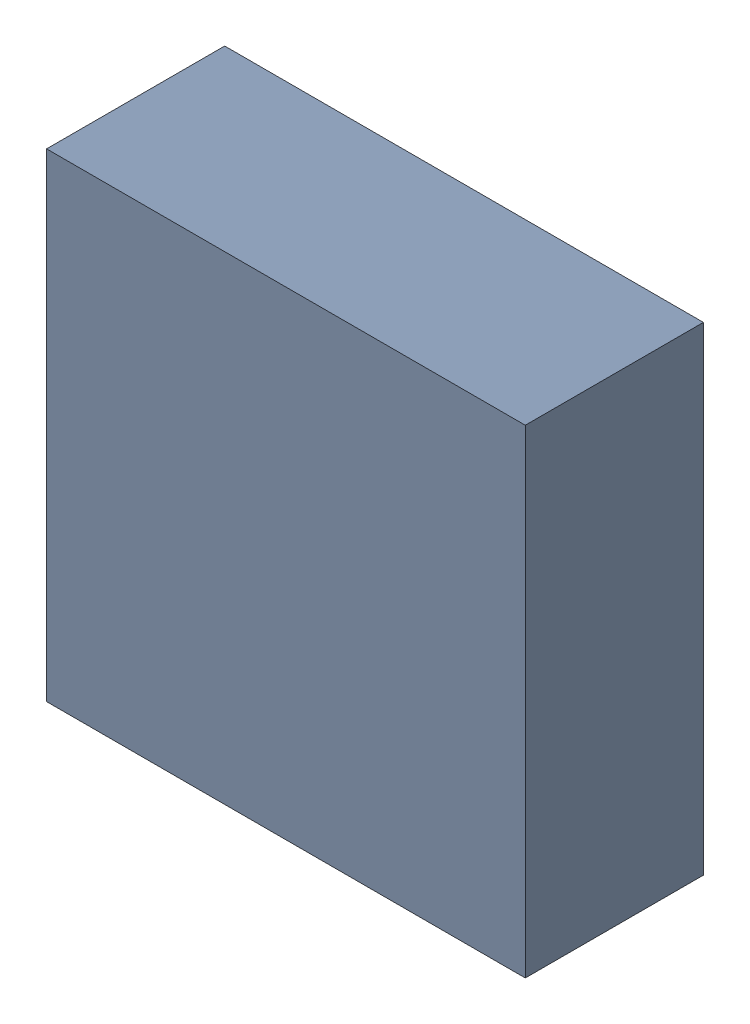
SolidWorks assembly Q1, configuration ﾃﾞﾌｫﾙﾄ. Lengths in mm.
Overall size (2.15 2.15 0.8).
2 component instances, 1 part files, 0 mates.
Components (placement in the parent):
- 689261240-1: 689261240 [ﾃﾞﾌｫﾙﾄ] at (5.3975 19.685 0) size (2.15 2.15 0.8)
  - Extruded_30-1: Extruded_30 [ﾃﾞﾌｫﾙﾄ] at origin size (2.15 2.15 0.8)
